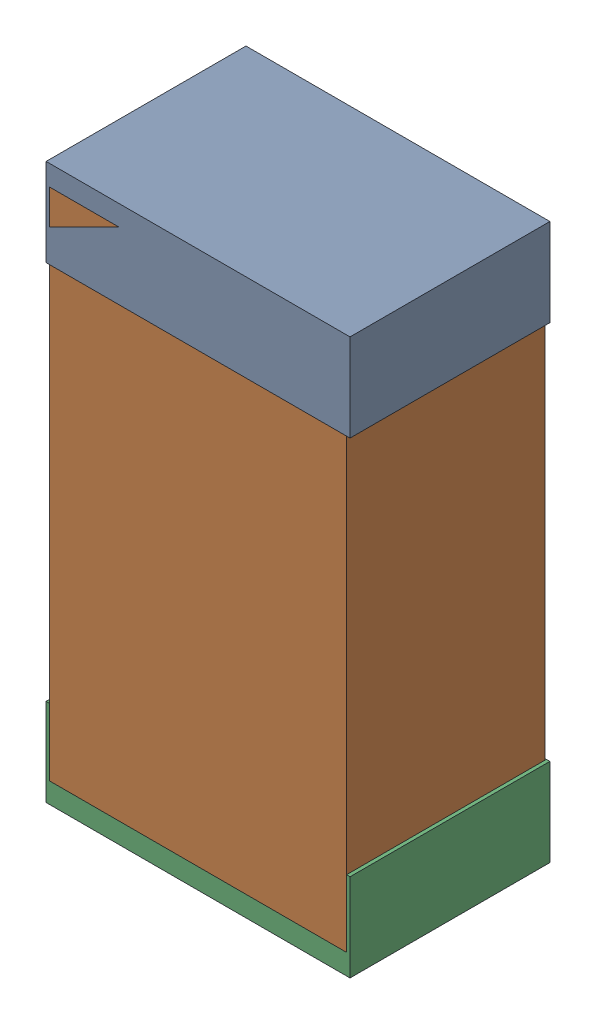
SolidWorks assembly R50Kanaloa_v2.0.0_Motor, configuration Default. Lengths in mm.
Overall size (1.3 2.38 0.85).
6 component instances, 2 part files, 0 mates.
Components (placement in the parent):
- 330415056-1: 330415056 [Default] at (92.964 149.336 -1.9574) size (1.3 0.38 0.85)
  - Extruded_2-1: Extruded_2 [Default] at origin size (1.3 0.38 0.85)
- 334787376-1: 334787376 [Default] at (92.964 148.336 -1.9524) size (1.27 2.2 0.85)
  - Extruded_16-1: Extruded_16 [Default] at origin size (1.27 2.2 0.85)
- 330415056-2: 330415056 [Default] at (92.964 147.336 -1.9574) size (1.3 0.38 0.85)
  - Extruded_2-1: Extruded_2 [Default] at origin size (1.3 0.38 0.85)
